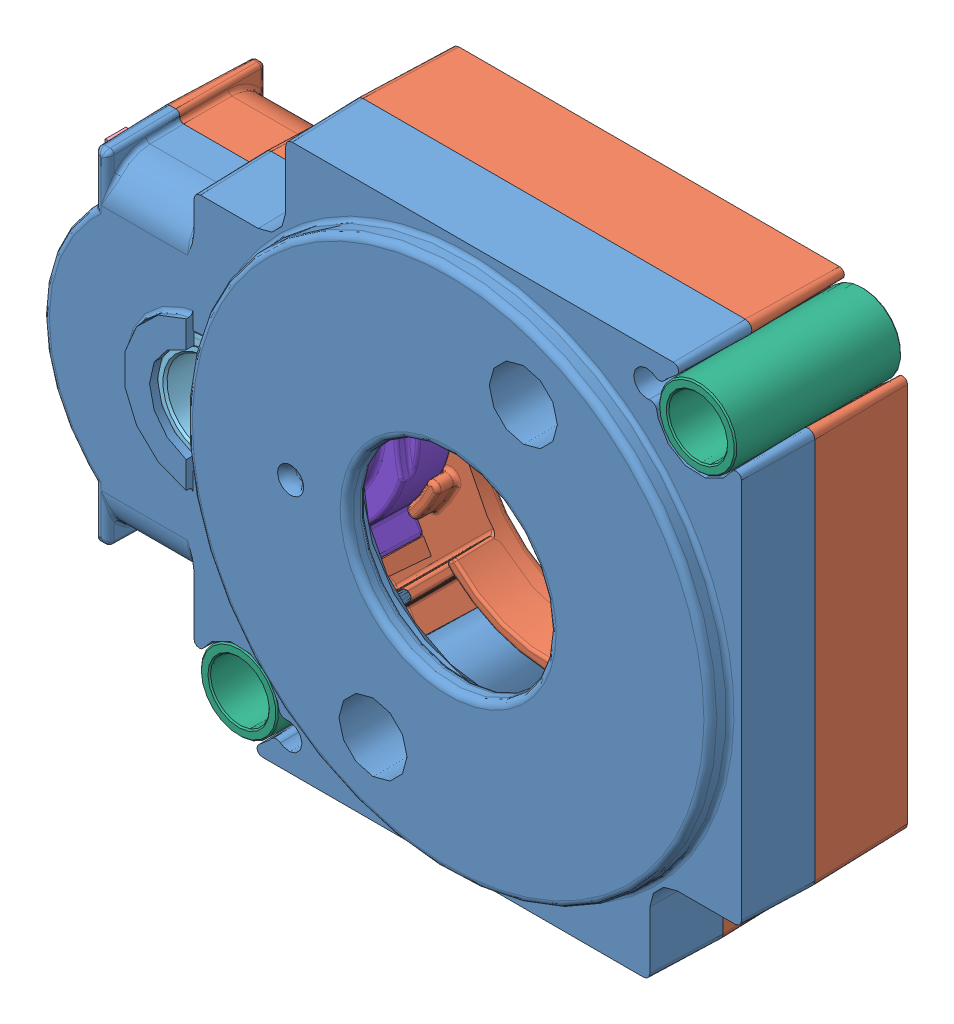
SolidWorks assembly VersaPlanetary_Integrated_Encoder_217-5046, configuration Default. Lengths in mm.
Overall size (58.21 43.13 18.16).
9 component instances, 8 part files, 0 mates.
Components (placement in the parent):
- 217-4783-001 Rev3-1: 217-4783-001 Rev3 [Default] at (0 0 2.75) size (53.55 42 11.11)
- 217-4783-002 Rev7_Sealed Config-1: 217-4783-002 Rev7_Sealed Config [Default] at (0 0 -7.2) x (0 1 0) z (0 0 1) size (42 51.56 9.32)
- 217-4783-008 Rev2-1: 217-4783-008 Rev2 [Default] at (-20.05 0 2.2) x (0.307149 -0.951661 0) z (0.951661 0.307149 0) size (5 4 5)
- PCBA Rev3-1: PCBA Rev3 [Default] at (-20.05 0 -2.1252) x (0 1 0) z (-1 0 0) size (15.93 10.15 24.58)
- 217-2788-001 Rev3_57155K375-1: 217-2788-001 Rev3_57155K375 [Default] at (-20.05 0 3.8125) x (-0.99574 0.092202 0) z (0 0 1) size (9.53 9.53 3.17)
- 217-4783-006 Rev3-1: 217-4783-006 Rev3 [Default] at (17.5 17.5 -0.85) x (-0.867641 0.497191 0) z (0 0 1) size (5.9 5.9 12.7)
- 217-4783-006 Rev3-2: 217-4783-006 Rev3 [Default] at (-17.5 -17.5 -0.85) x (0.825154 -0.564908 0) z (0 0 1) size (5.9 5.9 12.7)
- 217-4783-007 Rev1-1: 217-4783-007 Rev1 [Default] at (-16.45 0 -5.2) x (0 1 0) z (0 0 1) size (6 10.71 3.56)
- 217-4783-003 Rev4-1: 217-4783-003 Rev4 [Default] at (-20.05 0 -1.02) x (0 1 0) z (0 0 1) size (23.4 21.71 4.21)
